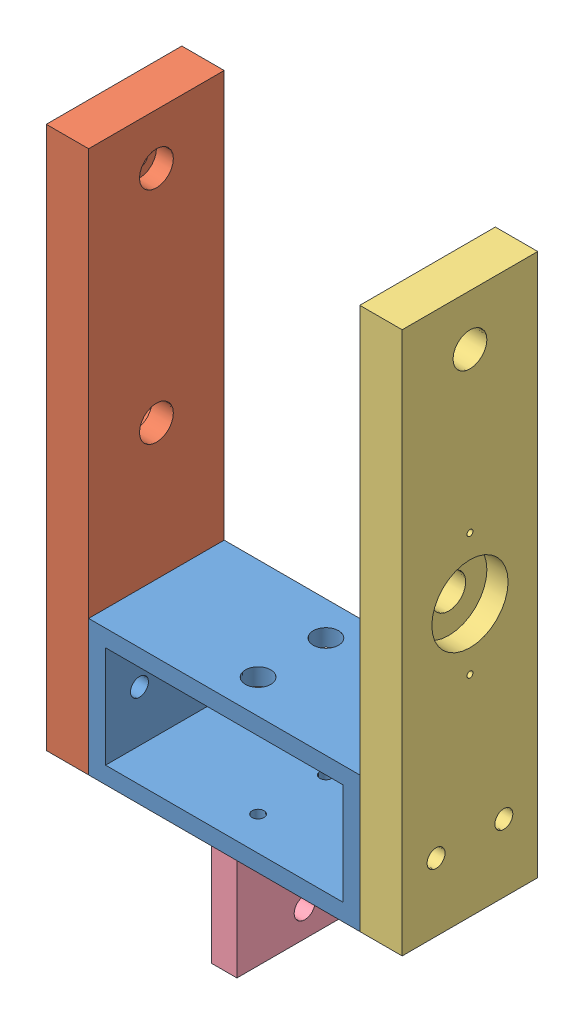
SolidWorks assembly Yoke, configuration Default. Lengths in mm.
Overall size (133.35 241.3 50.8).
4 component instances, 4 part files, 16 mates.
Components (placement in the parent):
- Yoke_Base-1: Yoke_Base [Default] x (0 0 -1) z (1 0 0) size (50.8 50.8 101.6)
- Yoke-Prong-1: Yoke-Prong [Default] at (-50.8 0 0) x (0 0 1) z (-1 0 0) size (50.8 203.2 15.88)
- Yoke_Prong_Encoder Side-1: Yoke_Prong_Encoder Side [Default] at (50.8 0 0) x (0 0 -1) z (1 0 0) size (50.8 203.2 15.88)
- Yoke_Base Mount-1: Yoke_Base Mount [Default] at (0 -25.4 0) x (0 0 1) z (0 -1 0) size (50.8 9.53 38.1)
Mates (geometry in assembly coordinates):
- InPlace1: in place: plane of Yoke_Base-1 through (0 0 0) normal (1 0 0); moOrthogonalPlaneRef_w of Yoke_Base-1 through (0 0 0) normal (0 1 0); plane of Yoke_Base-1 through (0 0 0) normal (0 0 -1); unknown of Yoke_Base-1
- Coincident1: coincident aligned: 
- Coincident2: coincident aligned: plane of Yoke_Base-1 through (0 0 0) normal (0 1 0)
- Coincident3: coincident anti-aligned: plane of Yoke_Base-1 through (0 0 0) normal (0 0 -1)
- InPlace2: in place: plane of Yoke_Base-1 through (-50.8 -25.4 -25.4) normal (-1 0 0); plane of Yoke-Prong-1 through (-50.8 0 0) normal (-1 0 0); plane of Yoke_Base-1 through (-50.8 -25.4 -25.4) normal (-1 0 0); plane of Yoke-Prong-1 through (-50.8 0 0) normal (0 1 0); plane of Yoke_Base-1 through (-50.8 -25.4 -25.4) normal (-1 0 0); plane of Yoke-Prong-1 through (-50.8 0 0) normal (0 0 1); plane of Yoke_Base-1 through (-50.8 -25.4 -25.4) normal (-1 0 0); unknown of Yoke-Prong-1
- Coincident4: coincident aligned: plane of Yoke_Base-1; plane of Yoke-Prong-1
- Coincident5: coincident aligned: moOrthogonalPlaneRef_w of Yoke_Base-1 through (-50.8 0 0) normal (0 1 0); plane of Yoke-Prong-1 through (-50.8 0 0) normal (0 1 0)
- Coincident6: coincident anti-aligned: moOrthogonalPlaneRef_w of Yoke_Base-1 through (-50.8 0 0) normal (0 0 -1); plane of Yoke-Prong-1 through (-50.8 0 0) normal (0 0 1)
- InPlace3: in place: plane of Yoke_Base-1 through (50.8 -25.4 -25.4) normal (1 0 0); plane of Yoke_Prong_Encoder Side-1 through (50.8 0 0) normal (1 0 0); plane of Yoke_Base-1 through (50.8 -25.4 -25.4) normal (1 0 0); plane of Yoke_Prong_Encoder Side-1 through (50.8 0 0) normal (0 1 0); plane of Yoke_Base-1 through (50.8 -25.4 -25.4) normal (1 0 0); plane of Yoke_Prong_Encoder Side-1 through (50.8 0 0) normal (0 0 -1); plane of Yoke_Base-1 through (50.8 -25.4 -25.4) normal (1 0 0); unknown of Yoke_Prong_Encoder Side-1
- Coincident1: coincident aligned: plane of Yoke_Base-1; plane of Yoke_Prong_Encoder Side-1
- Coincident2: coincident aligned: moOrthogonalPlaneRef_w of Yoke_Base-1 through (50.8 0 0) normal (0 1 0); plane of Yoke_Prong_Encoder Side-1 through (50.8 0 0) normal (0 1 0)
- Coincident3: coincident anti-aligned: moOrthogonalPlaneRef_w of Yoke_Base-1 through (50.8 0 0) normal (0 0 1); plane of Yoke_Prong_Encoder Side-1 through (50.8 0 0) normal (0 0 -1)
- InPlace4: in place: plane of Yoke_Base-1 through (50.8 -25.4 -25.4) normal (0 -1 0); plane of ? through (0 -25.4 0) normal (0 -1 0); plane of Yoke_Base-1 through (50.8 -25.4 -25.4) normal (0 -1 0); plane of ? through (0 -25.4 0) normal (0 0 -1); plane of Yoke_Base-1 through (50.8 -25.4 -25.4) normal (0 -1 0); plane of ? through (0 -25.4 0) normal (-1 0 0); plane of Yoke_Base-1 through (50.8 -25.4 -25.4) normal (0 -1 0); unknown of Yoke_Base Mount-1
- Coincident4: coincident aligned: plane of Yoke_Base-1; plane of Yoke_Base Mount-1
- Coincident5: coincident aligned: moOrthogonalPlaneRef_w of Yoke_Base-1 through (0 -25.4 0) normal (-1 0 0); plane of Yoke_Base Mount-1 through (0 -25.4 0) normal (-1 0 0)
- Coincident6: coincident anti-aligned: moOrthogonalPlaneRef_w of Yoke_Base-1 through (0 -25.4 0) normal (0 0 -1); plane of Yoke_Base Mount-1 through (0 -25.4 0) normal (0 0 1)
